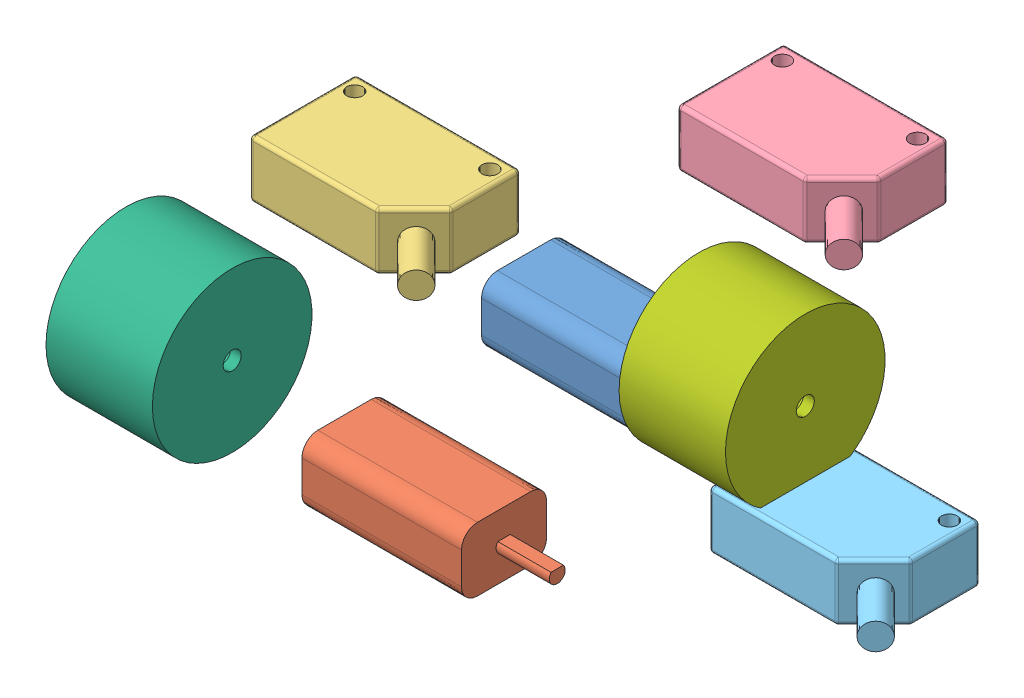
SolidWorks assembly Assem5, configuration Default. Lengths in mm.
Overall size (122.72 61.55 77.75).
7 component instances, 7 part files, 0 mates.
Components (placement in the parent):
- 16mm motor-1: 16mm motor [Default] at (10.2526 13.999 31.1283) size (40 12 16)
- 16mm motor 2-1: 16mm motor 2 [Default] at (-4.4019 -9.7567 50.2293) size (40 12 16)
- omron-1: omron [Default] at (-22.9817 26.8593 39.0209) size (37.72 10.8 25.16)
- omron2-1: omron2 [Default] at (26.3555 40.9964 7.9697) size (37.72 10.8 25.16)
- omron3-1: omron3 [Default] at (51.692 1.1777 27.3268) size (37.72 10.8 25.16)
- tekerlek-1: tekerlek [Default] at (-50.0071 11.0359 60.721) size (20 30 30)
- tekerlek2-1: tekerlek2 [Default] at (24.6189 24.3779 27.6273) size (20 30 30)
